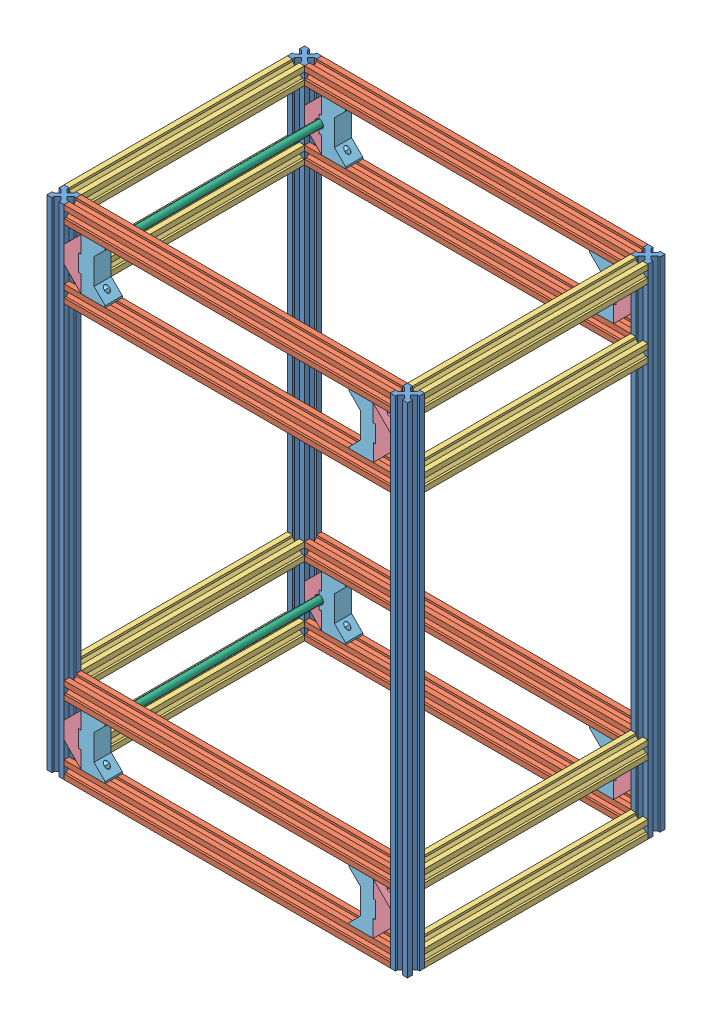
SolidWorks assembly chassis vide, configuration Défaut. Lengths in mm.
Overall size (420 580 300).
43 component instances, 6 part files, 11 mates.
Components (placement in the parent):
- module externe1.0-1: module externe1.0 [Défaut] at origin size (420 580 300)
  - base chassis horizontale-1: base chassis horizontale [Défaut] at (107.5488 34.6411 0) size (420 580 20)
    - profilé 580-1: profilé 580 [Défaut] at (-152.6624 -292.9685 550) size (20 580 20)
    - profilé 380-1: profilé 380 [Défaut] at (-152.6624 -272.9685 550) x (0 0 1) z (0 1 0) size (20 380 20)
    - profilé 380-2: profilé 380 [Défaut] at (227.3376 -212.9685 550) x (0 0 1) z (0 -1 0) size (20 380 20)
    - profilé 380-3: profilé 380 [Défaut] at (227.3376 267.0315 550) x (0 0 1) z (0 -1 0) size (20 380 20)
    - profilé 380-4: profilé 380 [Défaut] at (227.3376 187.0315 550) x (0 0 1) z (0 -1 0) size (20 380 20)
    - profilé 580-2: profilé 580 [Défaut] at (247.3376 -292.9685 530) x (0 0 -1) z (1 0 0) size (20 580 20)
  - profilé 260-1: profilé 260 [Défaut] at (-45.1136 -238.3275 550) x (0 1 0) z (1 0 0) size (20 260 20)
  - profilé 260-2: profilé 260 [Défaut] at (334.8864 -258.3275 810) x (-1 0 0) z (0 -1 0) size (20 260 20)
  - profilé 260-3: profilé 260 [Défaut] at (334.8864 321.6725 550) x (-1 0 0) z (0 1 0) size (20 260 20)
  - profilé 260-4: profilé 260 [Défaut] at (-65.1136 321.6725 550) x (-1 0 0) z (0 1 0) size (20 260 20)
  - base chassis horizontale-2: base chassis horizontale [Défaut] at (182.224 28.704 280) x (-1 0 0) z (0 0 1) size (420 580 20)
    - profilé 580-1: profilé 580 [Défaut] at (-152.6624 -292.9685 550) size (20 580 20)
    - profilé 380-1: profilé 380 [Défaut] at (-152.6624 -272.9685 550) x (0 0 1) z (0 1 0) size (20 380 20)
    - profilé 380-2: profilé 380 [Défaut] at (227.3376 -212.9685 550) x (0 0 1) z (0 -1 0) size (20 380 20)
    - profilé 380-3: profilé 380 [Défaut] at (227.3376 267.0315 550) x (0 0 1) z (0 -1 0) size (20 380 20)
    - profilé 380-4: profilé 380 [Défaut] at (227.3376 187.0315 550) x (0 0 1) z (0 -1 0) size (20 380 20)
    - profilé 580-2: profilé 580 [Défaut] at (247.3376 -292.9685 530) x (0 0 -1) z (1 0 0) size (20 580 20)
  - profilé 260-5: profilé 260 [Défaut] at (-65.1136 -158.3275 550) x (-1 0 0) z (0 1 0) size (20 260 20)
  - profilé 260-6: profilé 260 [Défaut] at (354.8864 -178.3275 550) x (1 0 0) z (0 -1 0) size (20 260 20)
  - profilé 260-7: profilé 260 [Défaut] at (334.8864 221.6725 810) x (-1 0 0) z (0 -1 0) size (20 260 20)
  - profilé 260-8: profilé 260 [Défaut] at (-45.1136 221.6725 810) x (0 -1 0) z (1 0 0) size (20 260 20)
- fin axe a v2.0-1: fin axe a v2.0 [Défaut] at (-45.1136 301.6725 810) x (0 -1 0) z (0 0 1) size (60 20 20)
- fin axe b v2.0-1: fin axe b v2.0 [Défaut] at (-25.2136 241.6725 830) x (0 1 0) z (0 0 -1) size (60 30.9 20)
- axe 8mm 290-5: axe 8mm 290 [Défaut] at (-28.1136 271.6725 535) size (8 8 290)
- fin axe a v2.0-2: fin axe a v2.0 [Défaut] at (-45.1136 241.6725 550) x (0 1 0) z (0 0 -1) size (60 20 20)
- fin axe b v2.0-2: fin axe b v2.0 [Défaut] at (-25.2136 301.6725 530) x (0 -1 0) z (0 0 1) size (60 30.9 20)
- fin axe b v2.0-9: fin axe b v2.0 [Défaut] at (314.9864 301.6725 830) x (0 -1 0) z (0 0 -1) size (60 30.9 20)
- fin axe a v2.0-9: fin axe a v2.0 [Défaut] at (334.8864 241.6725 810) x (0 1 0) z (0 0 1) size (60 20 20)
- axe 8mm 290-6: axe 8mm 290 [Défaut] at (317.8864 271.6725 825) x (-1 0 0) z (0 0 -1) size (8 8 290)
- fin axe b v2.0-10: fin axe b v2.0 [Défaut] at (314.9864 241.6725 530) x (0 1 0) z (0 0 1) size (60 30.9 20)
- fin axe a v2.0-10: fin axe a v2.0 [Défaut] at (334.8864 301.6725 550) x (0 -1 0) z (0 0 -1) size (60 20 20)
- fin axe b v2.0-11: fin axe b v2.0 [Défaut] at (-25.2136 -238.3275 830) x (0 1 0) z (0 0 -1) size (60 30.9 20)
- fin axe a v2.0-11: fin axe a v2.0 [Défaut] at (-45.1136 -178.3275 810) x (0 -1 0) z (0 0 1) size (60 20 20)
- axe 8mm 290-7: axe 8mm 290 [Défaut] at (-28.1136 -208.3275 825) x (1 0 0) z (0 0 -1) size (8 8 290)
- fin axe b v2.0-12: fin axe b v2.0 [Défaut] at (-25.2136 -178.3275 530) x (0 -1 0) z (0 0 1) size (60 30.9 20)
- fin axe a v2.0-12: fin axe a v2.0 [Défaut] at (-45.1136 -238.3275 550) x (0 1 0) z (0 0 -1) size (60 20 20)
- fin axe b v2.0-13: fin axe b v2.0 [Défaut] at (314.9864 -178.3275 830) x (0 -1 0) z (0 0 -1) size (60 30.9 20)
- fin axe a v2.0-13: fin axe a v2.0 [Défaut] at (334.8864 -238.3275 810) x (0 1 0) z (0 0 1) size (60 20 20)
- axe 8mm 290-8: axe 8mm 290 [Défaut] at (317.8864 -208.3275 535) x (-1 0 0) z (0 0 1) size (8 8 290)
- fin axe b v2.0-14: fin axe b v2.0 [Défaut] at (314.9864 -238.3275 530) x (0 1 0) z (0 0 1) size (60 30.9 20)
- fin axe a v2.0-14: fin axe a v2.0 [Défaut] at (334.8864 -178.3275 550) x (0 -1 0) z (0 0 -1) size (60 20 20)
Mates (geometry in assembly coordinates):
- Coïncidente42: coincident aligned: plane of module externe1.0-1 through (0 0 0) normal (0 0 1)
- Coïncidente43: coincident aligned: plane of module externe1.0-1 through (0 0 0) normal (0 1 0)
- Coïncidente44: coincident aligned: plane of module externe1.0-1 through (0 0 0) normal (1 0 0)
- Coïncidente62: coincident anti-aligned: plane of module externe1.0-1/base chassis horizontale-2/profilé 580-2 through (-45.1136 -258.3275 810) normal (1 0 0); plane of fin axe a v2.0-1 through (-45.1136 301.6725 825) normal (-1 0 0)
- Coïncidente63: coincident anti-aligned: line of module externe1.0-1/base chassis horizontale-2/profilé 580-2 through (-45.1136 -258.3275 810) axis (0 1 0); line of fin axe a v2.0-1 through (-45.1136 281.6725 810) axis (0 -1 0)
- Coïncidente64: coincident: plane of module externe1.0-1/base chassis horizontale-2/profilé 380-1 through (-45.1136 301.6725 830) normal (0 -1 0); line of fin axe a v2.0-1 through (-25.1136 301.6725 830) axis (0 0 -1)
- Coïncidente65: coincident anti-aligned: plane of fin axe a v2.0-1 through (-28.1136 301.6725 825) normal (1 0 0); plane of fin axe b v2.0-1 through (-28.1136 241.6725 825) normal (-1 0 0)
- Coïncidente66: coincident anti-aligned: line of fin axe a v2.0-1 through (-28.1136 281.6725 830) axis (0 -1 0); line of fin axe b v2.0-1 through (-28.1136 261.6725 830) axis (0 1 0)
- Coïncidente67: coincident anti-aligned: plane of module externe1.0-1/base chassis horizontale-2/profilé 380-2 through (334.8864 241.6725 830) normal (0 1 0); plane of fin axe b v2.0-1 through (-25.2136 241.6725 825) normal (0 -1 0)
- Coaxiale1: concentric anti-aligned: cylinder of fin axe a v2.0-2 through (-28.1136 271.6725 535) axis (0 0 1) radius 5; cylinder of axe 8mm 290-5 through (-28.1136 271.6725 825) axis (0 0 -1) radius 4
- Coïncidente68: coincident anti-aligned: plane of fin axe a v2.0-1 through (-45.1136 301.6725 825) normal (0 0 -1); plane of axe 8mm 290-5 through (-28.1136 271.6725 825) normal (0 0 1)
